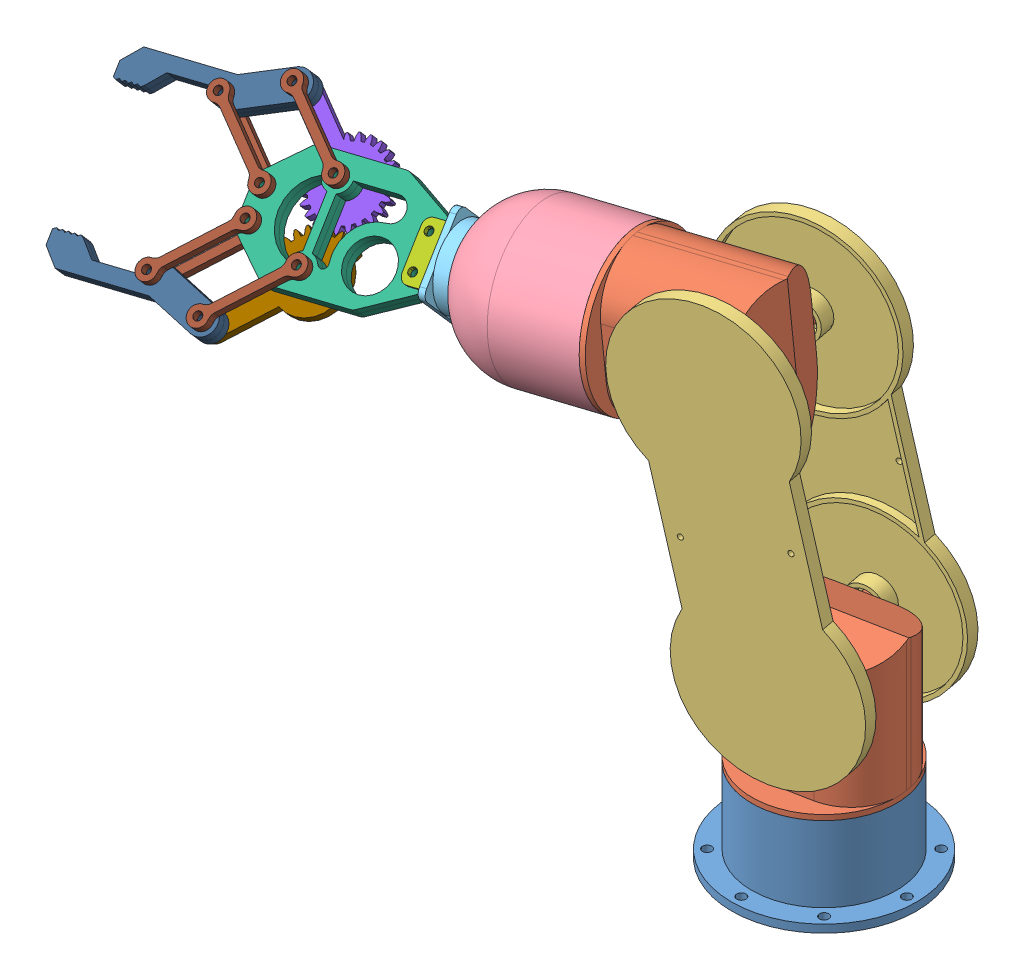
SolidWorks assembly Assem2, configuration Default. Lengths in mm.
Overall size (325.97 223.1 125.24).
23 component instances, 11 part files, 59 mates.
Components (placement in the parent):
- Base-1: Base [Default] at (30.2991 15.8227 66.5356) size (80 36.07 80)
- Hormbro-1: Hormbro [Default] at (30.2991 51.8966 66.5356) x (-0.190061 0 -0.981772) z (0.981772 0 -0.190061) size (62.59 62.27 62.59)
- Lateral-1: Lateral [Default] at (12.752 146.3391 38.6366) x (-0.232494 0.971556 0.045009) z (0.953847 0.236811 -0.184655) size (172.97 9.1 72.26)
- Lateral-3: Lateral [Default] at (24.4314 146.3391 98.9674) x (-0.232494 0.971556 0.045009) z (-0.953847 -0.236811 0.184655) size (172.97 9.1 72.26)
- Hormbro-2: Hormbro [Default] at (-37.5983 190.8878 79.6798) x (0.190061 0 0.981772) z (-0.094354 0.995371 0.018266) size (62.59 62.27 62.59)
- Rotor-1: Rotor [Default] at (-37.5983 190.8878 79.6798) x (0.15257 0.301385 0.941217) z (0.147473 -0.948647 0.279858) size (62.59 57.81 62.59)
- Arm 01 (1)-1: Arm 01 (1) [Default] at (-101.0165 184.6509 91.9569) x (0.204985 -0.657966 0.724611) z (-0.054836 -0.746889 -0.662683) size (31.8 9.83 31.58)
- Arm 03-1: Arm 03 [Default] at (-150.2805 178.5632 100.3188) x (0.204985 -0.657966 0.724611) z (0.977228 0.096106 -0.189181) size (46.66 3.41 70.55)
- Arm 03-2: Arm 03 [Default] at (-150.0933 181.1131 102.5811) x (0.204985 -0.657966 0.724611) z (0.977228 0.096106 -0.189181) size (46.66 3.41 70.55)
- Arm 02 (1)-1: Arm 02 (1) [Default] at (-104.2949 180.8096 89.3963) x (-0.204985 0.657966 -0.724611) z (-0.977228 -0.096106 0.189181) size (22.76 11.38 15.93)
- Arm 02 (1)-2: Arm 02 (1) [Default] at (-103.7745 187.8985 95.6861) x (0.204985 -0.657966 0.724611) z (-0.977228 -0.096106 0.189181) size (22.76 11.38 15.93)
- Arm 04-2: Arm 04 [Default] at (-156.1687 186.5842 86.6141) x (-0.857539 0.375204 -0.351921) z (-0.511488 -0.548979 0.661061) size (56.37 3.41 33.09)
- Arm 05-1: Arm 05 [Default] at (-148.6881 165.4794 109.7816) x (0.845693 0.318103 -0.428503) z (0.530845 -0.583924 0.614196) size (52.65 3.41 34.6)
- Arm 07-1: Arm 07 [Default] at (-196.4506 199.91 85.2317) x (-0.054836 -0.746889 -0.662683) z (0.829045 0.33583 -0.447105) size (3.41 24.46 68.29)
- Arm 07-2: Arm 07 [Default] at (-196.6378 197.3601 82.9694) x (-0.054836 -0.746889 -0.662683) z (0.829045 0.33583 -0.447105) size (3.41 24.46 68.29)
- Arm 07-3: Arm 07 [Default] at (-182.262 154.5142 135.2218) x (0.054836 0.746889 0.662683) z (0.982784 -0.157645 0.096353) size (3.41 24.46 68.29)
- Arm 07-4: Arm 07 [Default] at (-182.4492 151.9644 132.9594) x (0.054836 0.746889 0.662683) z (0.982784 -0.157645 0.096353) size (3.41 24.46 68.29)
- Arm 06-2: Arm 06 [Default] at (-182.9676 160.6205 118.0946) x (-0.578173 -0.517346 0.630927) z (0.81407 -0.417743 0.403462) size (43.24 3.41 7.97)
- Arm 06-3: Arm 06 [Default] at (-190.3446 184.2258 92.1002) x (-0.857539 0.375204 -0.351921) z (-0.511488 -0.548979 0.661061) size (43.24 3.41 7.97)
- Arm 06-4: Arm 06 [Default] at (-182.406 168.27 124.8817) x (-0.578173 -0.517346 0.630927) z (0.81407 -0.417743 0.403462) size (43.24 3.41 7.97)
- Arm 06-5: Arm 06 [Default] at (-189.7829 191.8753 98.8873) x (-0.857539 0.375204 -0.351921) z (-0.511488 -0.548979 0.661061) size (43.24 3.41 7.97)
- Arm 06-6: Arm 06 [Default] at (-157.8014 164.3232 127.2939) x (-0.578173 -0.517346 0.630927) z (0.81407 -0.417743 0.403462) size (43.24 3.41 7.97)
- Arm 06-7: Arm 06 [Default] at (-169.0273 200.283 87.6937) x (0.857539 -0.375204 0.351921) z (0.511488 0.548979 -0.661061) size (43.24 3.41 7.97)
Mates (geometry in assembly coordinates):
- Concentric1: concentric aligned: circle of Base-1; circle of Hormbro-1
- Coincident1: coincident anti-aligned: plane of Base-1 through (30.2991 51.8966 66.5356) normal (0 1 0); circle of Hormbro-1
- Concentric2: concentric anti-aligned: cylinder of Hormbro-1 through (25.3245 97.4158 40.8391) axis (0.190061 0 0.981772) radius 3.9829; cylinder of Lateral-1 through (26.1897 97.4158 45.3081) axis (-0.190061 0 -0.981772) radius 6.5434
- Coincident3: coincident anti-aligned: circle of Hormbro-1; plane of Lateral-1 through (26.1897 97.4158 45.3081) normal (0.190061 0 0.981772)
- Coincident5: coincident aligned: plane of Lateral-1 through (-18.3825 165.325 46.9821) normal (-0.953847 -0.236811 0.184655); plane of Lateral-3 through (-7.5682 165.325 102.844) normal (-0.953847 -0.236811 0.184655)
- Concentric3: concentric anti-aligned: circle of Hormbro-1; circle of Lateral-3
- Coincident6: coincident anti-aligned: circle of Hormbro-1; plane of Lateral-3 through (34.4085 97.4158 87.7631) normal (-0.190061 0 -0.981772)
- Concentric4: concentric anti-aligned: circle of Lateral-3; circle of Hormbro-2
- Coincident7: coincident anti-aligned: plane of Lateral-3 through (10.9937 195.2624 92.2959) normal (-0.190061 0 -0.981772); circle of Hormbro-2
- Coincident8: coincident aligned: plane of Hormbro-1 through (45.0223 111.982 85.7084) normal (0.190061 0 0.981772); plane of Hormbro-2 through (24.2081 207.4231 89.7378) normal (0.190061 0 0.981772)
- Concentric5: concentric aligned: cylinder of Rotor-1 through (-37.5983 190.8878 79.6798) axis (0.977228 0.096106 -0.189181) radius 29.0185; cylinder of Hormbro-2 through (-40.9345 190.5597 80.3257) axis (0.977228 0.096106 -0.189181) radius 28.4495
- Coincident9: coincident anti-aligned: plane of Hormbro-2 through (-37.5983 190.8878 79.6798) normal (-0.977228 -0.096106 0.189181); plane of Rotor-1 through (-33.171 199.6335 106.9925) normal (0.977228 0.096106 -0.189181)
- Coincident10: coincident anti-aligned: plane of Rotor-1 through (-91.3341 190.7783 107.6251) normal (-0.977228 -0.096106 0.189181); plane of Arm 01 (1)-1 through (-94.0913 185.3319 90.6163) normal (0.977228 0.096106 -0.189181)
- Concentric6: concentric aligned: circle of Rotor-1; circle of Arm 01 (1)-1
- Coincident17: coincident aligned: plane of Arm 03-1 through (-176.4889 168.5235 111.227) normal (-0.977228 -0.096106 0.189181); plane of Arm 03-2 through (-176.3017 171.0734 113.4894) normal (-0.977228 -0.096106 0.189181)
- Coincident19: coincident anti-aligned: plane of Arm 03-1 through (-151.0332 179.732 101.6396) normal (0.054836 0.746889 0.662683); plane of Arm 03-2 through (-151.0332 179.732 101.6396) normal (-0.054836 -0.746889 -0.662683)
- Coincident20: coincident aligned: plane of Arm 03-1 through (-176.4889 168.5235 111.227) normal (-0.485794 -0.55988 0.671221); plane of Arm 03-2 through (-176.3017 171.0734 113.4894) normal (-0.485794 -0.55988 0.671221)
- Coincident22: coincident anti-aligned: plane of Arm 01 (1)-1 through (-103.3808 200.9912 90.3106) normal (-0.977228 -0.096106 0.189181); plane of Arm 02 (1)-1 through (-104.5209 181.8426 74.6936) normal (0.977228 0.096106 -0.189181)
- Coincident23: coincident anti-aligned: plane of Arm 01 (1)-1 through (-106.7587 181.55 75.2086) normal (0.054836 0.746889 0.662683); plane of Arm 02 (1)-1 through (-106.745 181.6239 75.1242) normal (-0.054836 -0.746889 -0.662683)
- Width4: width anti-aligned: plane of Arm 02 (1)-1 through (-106.9402 190.0428 82.824) normal (-0.204985 0.657966 -0.724611); plane of Arm 02 (1)-1 through (-102.4456 172.7418 97.2521) normal (0.204985 -0.657966 0.724611); plane of Arm 01 (1)-1 through (-107.2795 186.4228 74.9938) normal (0.204985 -0.657966 0.724611); plane of Arm 01 (1)-1 through (-101.236 167.0242 96.3573) normal (-0.204985 0.657966 -0.724611)
- Coincident24: coincident anti-aligned: plane of Arm 01 (1)-1 through (-105.2529 202.0592 93.4055) normal (-0.054836 -0.746889 -0.662683); plane of Arm 02 (1)-2 through (-100.5739 187.158 109.813) normal (0.054836 0.746889 0.662683)
- Coincident25: coincident anti-aligned: plane of Arm 01 (1)-1 through (-103.3808 200.9912 90.3106) normal (-0.977228 -0.096106 0.189181); plane of Arm 02 (1)-2 through (-98.3498 187.3767 109.3824) normal (0.977228 0.096106 -0.189181)
- Width5: width anti-aligned: plane of Arm 02 (1)-2 through (-106.5576 195.2529 87.4467) normal (-0.204985 0.657966 -0.724611); plane of Arm 02 (1)-2 through (-101.0271 180.9845 104.3355) normal (0.204985 -0.657966 0.724611); plane of Arm 01 (1)-1 through (-107.2795 186.4228 74.9938) normal (0.204985 -0.657966 0.724611); plane of Arm 01 (1)-1 through (-101.236 167.0242 96.3573) normal (-0.204985 0.657966 -0.724611)
- Concentric17: concentric anti-aligned: cylinder of Arm 03-1 through (-115.2549 185.3493 87.1962) axis (0.054836 0.746889 0.662683) radius 1.707; cylinder of Arm 02 (1)-1 through (-114.6973 192.9436 93.9343) axis (-0.054836 -0.746889 -0.662683) radius 1.707
- Concentric18: concentric anti-aligned: cylinder of Arm 03-1 through (-112.4556 176.3643 97.0913) axis (0.054836 0.746889 0.662683) radius 1.707; cylinder of Arm 02 (1)-1 through (-111.8981 183.9586 103.8294) axis (-0.054836 -0.746889 -0.662683) radius 1.707
- Width6: width anti-aligned: plane of Arm 03-1 through (-151.2204 177.1821 99.3773) normal (-0.054836 -0.746889 -0.662683); plane of Arm 03-2 through (-150.8459 182.2818 103.902) normal (0.054836 0.746889 0.662683); plane of Arm 02 (1)-1 through (-106.121 190.1233 82.6654) normal (0.054836 0.746889 0.662683); plane of Arm 02 (1)-2 through (-101.1979 178.6586 102.2718) normal (-0.054836 -0.746889 -0.662683)
- Coincident26: coincident anti-aligned: plane of Arm 03-1 through (-151.2204 177.1821 99.3773) normal (-0.054836 -0.746889 -0.662683); plane of Arm 04-2 through (-168.4802 185.9131 90.9651) normal (0.054836 0.746889 0.662683)
- Concentric19: concentric aligned: cylinder of Arm 03-1 through (-154.3695 187.2903 88.2453) axis (0.054836 0.746889 0.662683) radius 1.707; cylinder of Arm 04-2 through (-154.5567 184.7405 85.9829) axis (0.054836 0.746889 0.662683) radius 1.707
- Coincident27: coincident anti-aligned: plane of Arm 03-1 through (-151.2204 177.1821 99.3773) normal (-0.054836 -0.746889 -0.662683); plane of Arm 05-1 through (-148.0712 167.074 110.5093) normal (0.054836 0.746889 0.662683)
- Concentric20: concentric anti-aligned: cylinder of Arm 03-1 through (-148.0712 167.074 110.5093) axis (0.054836 0.746889 0.662683) radius 1.707; cylinder of Arm 05-1 through (-148.0712 167.074 110.5093) axis (-0.054836 -0.746889 -0.662683) radius 1.707
- Coincident28: coincident anti-aligned: plane of Arm 07-1 through (-194.8118 198.8725 83.6895) normal (-0.054836 -0.746889 -0.662683); plane of Arm 07-2 through (-194.8118 198.8725 83.6895) normal (0.054836 0.746889 0.662683)
- Concentric21: concentric aligned: cylinder of Arm 07-1 through (-184.434 203.0764 78.0928) axis (0.054836 0.746889 0.662683) radius 1.707; cylinder of Arm 07-2 through (-184.6212 200.5265 75.8304) axis (0.054836 0.746889 0.662683) radius 1.707
- Concentric22: concentric aligned: cylinder of Arm 07-1 through (-205.1896 194.6687 89.2863) axis (0.054836 0.746889 0.662683) radius 1.707; cylinder of Arm 07-2 through (-205.3768 192.1188 87.0239) axis (0.054836 0.746889 0.662683) radius 1.707
- Coincident31: coincident aligned: plane of Arm 03-1 through (-151.2204 177.1821 99.3773) normal (-0.054836 -0.746889 -0.662683); plane of Arm 07-2 through (-194.999 196.3227 81.4272) normal (-0.054836 -0.746889 -0.662683)
- Concentric24: concentric aligned: cylinder of Arm 04-2 through (-184.8084 197.9767 73.5681) axis (0.054836 0.746889 0.662683) radius 1.707; cylinder of Arm 07-2 through (-184.6212 200.5265 75.8304) axis (0.054836 0.746889 0.662683) radius 1.707
- Coincident32: coincident anti-aligned: plane of Arm 07-3 through (-180.5827 153.3465 133.823) normal (-0.054836 -0.746889 -0.662683); plane of Arm 07-4 through (-180.5827 153.3465 133.823) normal (0.054836 0.746889 0.662683)
- Concentric25: concentric aligned: cylinder of Arm 07-3 through (-168.0932 153.923 137.2915) axis (-0.054836 -0.746889 -0.662683) radius 5.6899; cylinder of Arm 07-4 through (-168.2804 151.3732 135.0291) axis (-0.054836 -0.746889 -0.662683) radius 5.6899
- Coincident33: coincident anti-aligned: circle of Arm 07-3; cylinder of Arm 07-4 through (-192.885 155.3199 132.6168) axis (-0.054836 -0.746889 -0.662683) radius 1.707
- Coincident35: coincident aligned: plane of Arm 03-1 through (-151.2204 177.1821 99.3773) normal (-0.054836 -0.746889 -0.662683); plane of Arm 07-4 through (-180.7699 150.7967 131.5606) normal (-0.054836 -0.746889 -0.662683)
- Concentric26: concentric aligned: cylinder of Arm 05-1 through (-168.4676 148.8233 132.7667) axis (-0.054836 -0.746889 -0.662683) radius 1.707; cylinder of Arm 07-4 through (-168.2804 151.3732 135.0291) axis (-0.054836 -0.746889 -0.662683) radius 1.707
- Concentric29: concentric aligned: cylinder of Arm 03-1 through (-172.6758 171.0207 108.097) axis (0.054836 0.746889 0.662683) radius 1.707; cylinder of Arm 06-2 through (-172.863 168.4709 105.8347) axis (0.054836 0.746889 0.662683) radius 1.707
- Concentric30: concentric anti-aligned: cylinder of Arm 07-4 through (-192.885 155.3199 132.6168) axis (-0.054836 -0.746889 -0.662683) radius 1.707; cylinder of Arm 06-2 through (-193.2594 150.2202 128.0921) axis (0.054836 0.746889 0.662683) radius 1.707
- Coincident36: coincident anti-aligned: plane of Arm 03-1 through (-151.2204 177.1821 99.3773) normal (-0.054836 -0.746889 -0.662683); plane of Arm 06-2 through (-182.874 161.8954 119.2258) normal (0.054836 0.746889 0.662683)
- Concentric31: concentric anti-aligned: circle of Arm 03-1; cylinder of Arm 06-3 through (-175.3123 176.3328 97.1764) axis (0.054836 0.746889 0.662683) radius 1.707
- Concentric32: concentric aligned: cylinder of Arm 07-2 through (-205.3768 192.1188 87.0239) axis (0.054836 0.746889 0.662683) radius 1.707; cylinder of Arm 06-3 through (-205.564 189.569 84.7616) axis (0.054836 0.746889 0.662683) radius 1.707
- Coincident37: coincident anti-aligned: plane of Arm 03-1 through (-151.2204 177.1821 99.3773) normal (-0.054836 -0.746889 -0.662683); plane of Arm 06-3 through (-190.251 185.5007 93.2314) normal (0.054836 0.746889 0.662683)
- Concentric33: concentric aligned: circle of Arm 06-2; circle of Arm 06-4
- Concentric34: concentric aligned: circle of Arm 06-2; circle of Arm 06-4
- Coincident38: coincident anti-aligned: plane of Arm 07-3 through (-180.3955 155.8964 136.0853) normal (0.054836 0.746889 0.662683); plane of Arm 06-4 through (-182.4996 166.9951 123.7505) normal (-0.054836 -0.746889 -0.662683)
- Concentric35: concentric aligned: cylinder of Arm 06-3 through (-175.3123 176.3328 97.1764) axis (0.054836 0.746889 0.662683) radius 1.707; cylinder of Arm 06-5 through (-174.7507 183.9823 103.9635) axis (0.054836 0.746889 0.662683) radius 1.707
- Concentric36: concentric aligned: cylinder of Arm 06-3 through (-205.564 189.569 84.7616) axis (0.054836 0.746889 0.662683) radius 1.707; cylinder of Arm 06-5 through (-205.0024 197.2185 91.5487) axis (0.054836 0.746889 0.662683) radius 1.707
- Coincident40: coincident anti-aligned: plane of Arm 07-1 through (-194.6246 201.4223 85.9519) normal (0.054836 0.746889 0.662683); plane of Arm 06-5 through (-189.8766 190.6004 97.7561) normal (-0.054836 -0.746889 -0.662683)
- Concentric37: concentric anti-aligned: circle of Arm 05-1; circle of Arm 06-6
- Concentric38: concentric anti-aligned: circle of Arm 05-1; circle of Arm 06-6
- Coincident41: coincident anti-aligned: plane of Arm 03-2 through (-150.8459 182.2818 103.902) normal (0.054836 0.746889 0.662683); plane of Arm 06-6 through (-157.895 163.0483 126.1627) normal (-0.054836 -0.746889 -0.662683)
- Coincident42: coincident anti-aligned: plane of Arm 03-2 through (-150.8459 182.2818 103.902) normal (0.054836 0.746889 0.662683); plane of Arm 06-7 through (-169.1209 199.0081 86.5626) normal (-0.054836 -0.746889 -0.662683)
- Coincident43: coincident anti-aligned: circle of Arm 04-2; cylinder of Arm 06-7 through (-153.9951 192.39 92.77) axis (0.054836 0.746889 0.662683) radius 1.707
- Concentric39: concentric aligned: circle of Arm 04-2; circle of Arm 06-7
- GearMate1: gear = 3.4139 : 3.4139 mm: circle of Arm 04-2; circle of Arm 05-1
